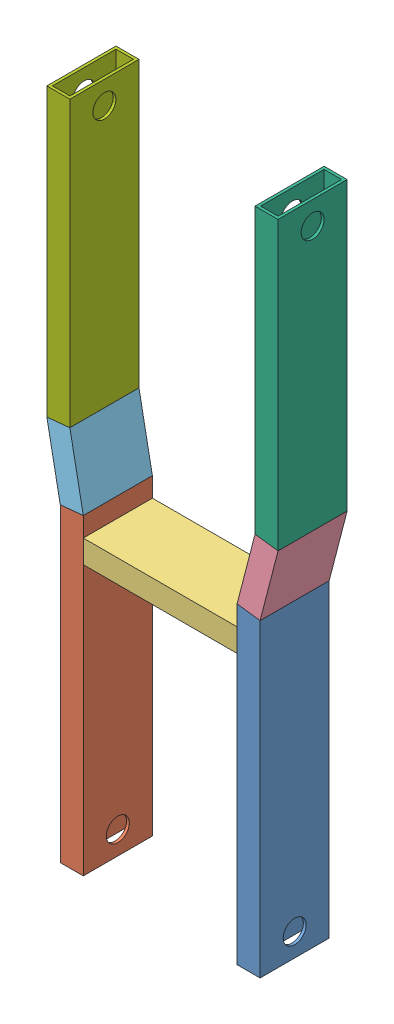
SolidWorks assembly Swing Arm Assembly, configuration Default. Lengths in mm.
Overall size (255 763.84 76.2).
8 component instances, 8 part files, 21 mates.
Components (placement in the parent):
- Outline Sketch-1: Outline Sketch [Default] at (95.7159 69.1507 541.8075) size (229.6 763.84 0)
- D1-2: D1 [Default] at (290.7159 69.1507 541.8075) x (1 0 0) z (0 1 0) size (25.4 76.2 344.62)
- D2-2: D2 [Default] at (95.7159 69.1507 541.8075) x (1 0 0) z (0 1 0) size (25.4 76.2 344.22)
- D5-1: D5 [Default] at (290.7159 379.1507 541.8075) x (0 -1 0) z (-1 0 0) size (25.4 76.2 182.3)
- D7-1: D7 [Default] at (290.7159 412.1507 541.8075) x (0.96807 -0.25068 0) z (0.25068 0.96807 0) size (25.4 76.2 82.22)
- D6-1: D6 [Default] at (95.7159 412.1507 541.8075) x (-0.981778 -0.19003 0) z (-0.19003 0.981778 0) size (25.4 76.2 80.32)
- D3-1: D3 [Default] at (310.5159 488.6138 541.8075) x (-1 0 0) z (0 1 0) size (25.4 76.2 316.62)
- D4-1: D4 [Default] at (80.9159 488.6138 541.8075) x (-1 0 0) z (0 1 0) size (25.4 76.2 316.22)
Mates (geometry in assembly coordinates):
- Coincident8: coincident: point of Outline Sketch-1; point of D1-2
- Parallel3: parallel anti-aligned: line of Outline Sketch-1 through (290.7159 69.1507 541.8075) axis (0 1 0); line of D1-2 through (303.4159 410.533 503.7075) axis (0 -1 0)
- Coincident11: coincident: point of Outline Sketch-1; point of D2-2
- Parallel4: parallel anti-aligned: line of Outline Sketch-1 through (95.7159 69.1507 541.8075) axis (0 1 0); line of D2-2 through (108.4159 413.3684 579.9075) axis (0 -1 0)
- Parallel5: parallel aligned: line of Outline Sketch-1 through (95.7159 412.1507 541.8075) axis (1 0 0); line of D5-1 through (108.4159 366.4507 503.7075) axis (1 0 0)
- Coincident15: coincident: point of Outline Sketch-1; point of D7-1
- Parallel6: parallel anti-aligned: line of Outline Sketch-1 through (290.7159 412.1507 541.8075) axis (0.25068 0.96807 0); line of D7-1 through (323.2159 486.9961 503.7075) axis (-0.25068 -0.96807 0)
- Coincident17: coincident: point of Outline Sketch-1; point of D6-1
- Parallel7: parallel aligned: line of Outline Sketch-1 through (80.9159 488.6138 541.8075) axis (0.19003 -0.981778 0); line of D6-1 through (93.6159 489.8316 503.7075) axis (0.19003 -0.981778 0)
- Coincident19: coincident: point of Outline Sketch-1; point of D3-1
- Parallel8: parallel aligned: line of Outline Sketch-1 through (310.5159 803.6138 541.8075) axis (0 -1 0); line of D3-1 through (297.8159 803.6138 579.9075) axis (0 -1 0)
- Coincident23: coincident: point of Outline Sketch-1; point of D4-1
- Parallel10: parallel aligned: line of Outline Sketch-1 through (80.9159 803.6138 541.8075) axis (0 -1 0); line of D4-1 through (93.6159 803.6138 579.9075) axis (0 -1 0)
- Parallel11: parallel anti-aligned: plane of D4-1 through (68.2159 803.6138 541.8075) normal (-1 0 0)
- Parallel12: parallel anti-aligned: plane of D3-1 through (297.8159 803.6138 541.8075) normal (-1 0 0)
- Parallel13: parallel anti-aligned: plane of D2-2 through (83.0159 412.1507 541.8075) normal (-1 0 0)
- Parallel14: parallel anti-aligned: plane of D1-2 through (278.0159 412.1507 541.8075) normal (-1 0 0)
- Parallel15: parallel anti-aligned: plane of D6-1 through (80.9159 488.6138 503.7075) normal (0 0 -1)
- Parallel16: parallel anti-aligned: plane of D7-1 through (310.5159 488.6138 503.7075) normal (0 0 -1)
- Coincident31: coincident aligned: plane of D1-2 through (290.7159 412.1507 579.9075) normal (0 0 1); plane of D5-1 through (95.7159 379.1507 579.9075) normal (0 0 1)
- Coincident32: coincident: point of Outline Sketch-1; point of D5-1
